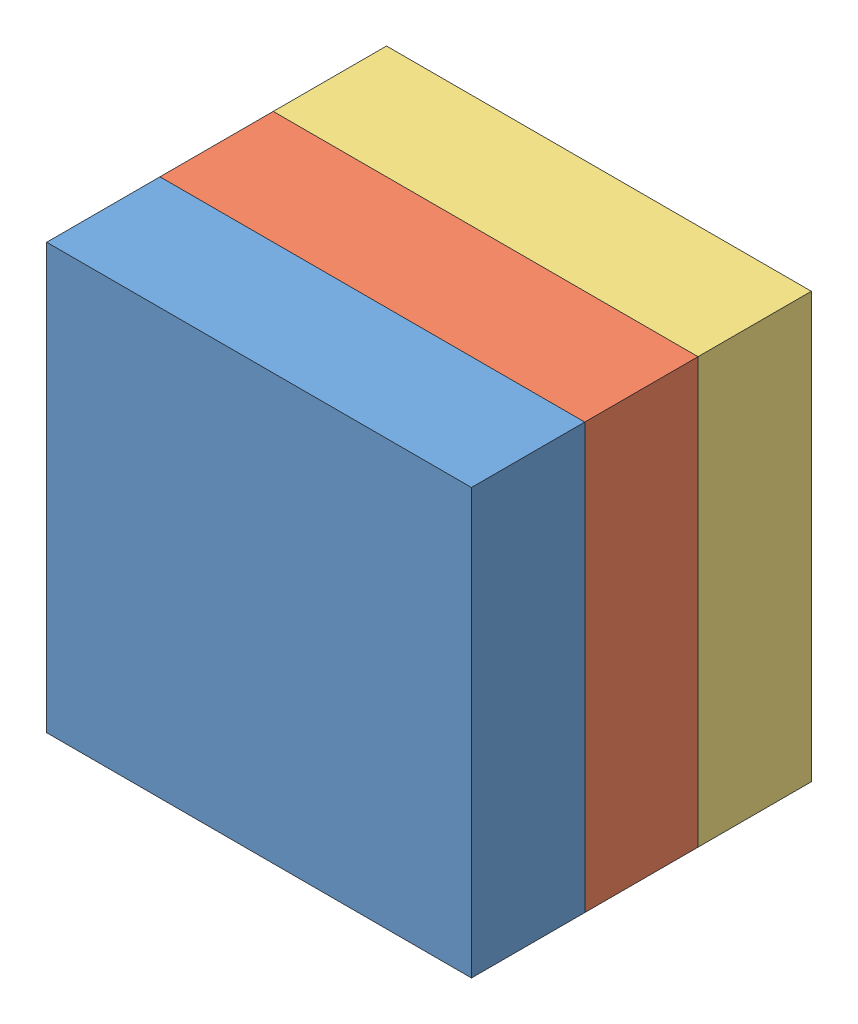
SolidWorks assembly Montagem Molde, configuration Valor predeterminado. Lengths in mm.
Overall size (150 150 120).
147 component instances, 4 part files, 12 mates.
Components (placement in the parent):
- Placa Móvel-1: Placa Móvel [Valor predeterminado] at (-150 0 -40) size (150 150 40)
- Placa Flutuante-1: Placa Flutuante [Valor predeterminado] at (-150 0 -80) size (150 150 40)
- Placa Fixa-1: Placa Fixa [Valor predeterminado] at (-150 0 -120) size (150 150 40)
- Espaçador Escala Maior-1: Espaçador Escala Maior [Valor predeterminado] at (-138.25 138.25 -40) x (1 0 0) z (0 1 0) size (8.16 8.67 8.16)
- Espaçador Escala Maior-2: Espaçador Escala Maior [Valor predeterminado] at (-126.75 138.25 -40) x (1 0 0) z (0 1 0) size (8.16 8.67 8.16)
- Espaçador Escala Maior-3: Espaçador Escala Maior [Valor predeterminado] at (-115.25 138.25 -40) x (1 0 0) z (0 1 0) size (8.16 8.67 8.16)
- Espaçador Escala Maior-4: Espaçador Escala Maior [Valor predeterminado] at (-103.75 138.25 -40) x (1 0 0) z (0 1 0) size (8.16 8.67 8.16)
- Espaçador Escala Maior-5: Espaçador Escala Maior [Valor predeterminado] at (-92.25 138.25 -40) x (1 0 0) z (0 1 0) size (8.16 8.67 8.16)
- Espaçador Escala Maior-6: Espaçador Escala Maior [Valor predeterminado] at (-80.75 138.25 -40) x (1 0 0) z (0 1 0) size (8.16 8.67 8.16)
- Espaçador Escala Maior-7: Espaçador Escala Maior [Valor predeterminado] at (-69.25 138.25 -40) x (1 0 0) z (0 1 0) size (8.16 8.67 8.16)
- Espaçador Escala Maior-8: Espaçador Escala Maior [Valor predeterminado] at (-57.75 138.25 -40) x (1 0 0) z (0 1 0) size (8.16 8.67 8.16)
- Espaçador Escala Maior-9: Espaçador Escala Maior [Valor predeterminado] at (-46.25 138.25 -40) x (1 0 0) z (0 1 0) size (8.16 8.67 8.16)
- Espaçador Escala Maior-10: Espaçador Escala Maior [Valor predeterminado] at (-34.75 138.25 -40) x (1 0 0) z (0 1 0) size (8.16 8.67 8.16)
- Espaçador Escala Maior-11: Espaçador Escala Maior [Valor predeterminado] at (-23.25 138.25 -40) x (1 0 0) z (0 1 0) size (8.16 8.67 8.16)
- Espaçador Escala Maior-12: Espaçador Escala Maior [Valor predeterminado] at (-11.75 138.25 -40) x (1 0 0) z (0 1 0) size (8.16 8.67 8.16)
- Espaçador Escala Maior-13: Espaçador Escala Maior [Valor predeterminado] at (-138.25 126.75 -40) x (1 0 0) z (0 1 0) size (8.16 8.67 8.16)
- Espaçador Escala Maior-14: Espaçador Escala Maior [Valor predeterminado] at (-126.75 126.75 -40) x (1 0 0) z (0 1 0) size (8.16 8.67 8.16)
- Espaçador Escala Maior-15: Espaçador Escala Maior [Valor predeterminado] at (-115.25 126.75 -40) x (1 0 0) z (0 1 0) size (8.16 8.67 8.16)
- Espaçador Escala Maior-16: Espaçador Escala Maior [Valor predeterminado] at (-103.75 126.75 -40) x (1 0 0) z (0 1 0) size (8.16 8.67 8.16)
- Espaçador Escala Maior-17: Espaçador Escala Maior [Valor predeterminado] at (-92.25 126.75 -40) x (1 0 0) z (0 1 0) size (8.16 8.67 8.16)
- Espaçador Escala Maior-18: Espaçador Escala Maior [Valor predeterminado] at (-80.75 126.75 -40) x (1 0 0) z (0 1 0) size (8.16 8.67 8.16)
- Espaçador Escala Maior-19: Espaçador Escala Maior [Valor predeterminado] at (-69.25 126.75 -40) x (1 0 0) z (0 1 0) size (8.16 8.67 8.16)
- Espaçador Escala Maior-20: Espaçador Escala Maior [Valor predeterminado] at (-57.75 126.75 -40) x (1 0 0) z (0 1 0) size (8.16 8.67 8.16)
- Espaçador Escala Maior-21: Espaçador Escala Maior [Valor predeterminado] at (-46.25 126.75 -40) x (1 0 0) z (0 1 0) size (8.16 8.67 8.16)
- Espaçador Escala Maior-22: Espaçador Escala Maior [Valor predeterminado] at (-34.75 126.75 -40) x (1 0 0) z (0 1 0) size (8.16 8.67 8.16)
- Espaçador Escala Maior-23: Espaçador Escala Maior [Valor predeterminado] at (-23.25 126.75 -40) x (1 0 0) z (0 1 0) size (8.16 8.67 8.16)
- Espaçador Escala Maior-24: Espaçador Escala Maior [Valor predeterminado] at (-11.75 126.75 -40) x (1 0 0) z (0 1 0) size (8.16 8.67 8.16)
- Espaçador Escala Maior-25: Espaçador Escala Maior [Valor predeterminado] at (-138.25 115.25 -40) x (1 0 0) z (0 1 0) size (8.16 8.67 8.16)
- Espaçador Escala Maior-26: Espaçador Escala Maior [Valor predeterminado] at (-126.75 115.25 -40) x (1 0 0) z (0 1 0) size (8.16 8.67 8.16)
- Espaçador Escala Maior-27: Espaçador Escala Maior [Valor predeterminado] at (-115.25 115.25 -40) x (1 0 0) z (0 1 0) size (8.16 8.67 8.16)
- Espaçador Escala Maior-28: Espaçador Escala Maior [Valor predeterminado] at (-103.75 115.25 -40) x (1 0 0) z (0 1 0) size (8.16 8.67 8.16)
- Espaçador Escala Maior-29: Espaçador Escala Maior [Valor predeterminado] at (-92.25 115.25 -40) x (1 0 0) z (0 1 0) size (8.16 8.67 8.16)
- Espaçador Escala Maior-30: Espaçador Escala Maior [Valor predeterminado] at (-80.75 115.25 -40) x (1 0 0) z (0 1 0) size (8.16 8.67 8.16)
- Espaçador Escala Maior-31: Espaçador Escala Maior [Valor predeterminado] at (-69.25 115.25 -40) x (1 0 0) z (0 1 0) size (8.16 8.67 8.16)
- Espaçador Escala Maior-32: Espaçador Escala Maior [Valor predeterminado] at (-57.75 115.25 -40) x (1 0 0) z (0 1 0) size (8.16 8.67 8.16)
- Espaçador Escala Maior-33: Espaçador Escala Maior [Valor predeterminado] at (-46.25 115.25 -40) x (1 0 0) z (0 1 0) size (8.16 8.67 8.16)
- Espaçador Escala Maior-34: Espaçador Escala Maior [Valor predeterminado] at (-34.75 115.25 -40) x (1 0 0) z (0 1 0) size (8.16 8.67 8.16)
- Espaçador Escala Maior-35: Espaçador Escala Maior [Valor predeterminado] at (-23.25 115.25 -40) x (1 0 0) z (0 1 0) size (8.16 8.67 8.16)
- Espaçador Escala Maior-36: Espaçador Escala Maior [Valor predeterminado] at (-11.75 115.25 -40) x (1 0 0) z (0 1 0) size (8.16 8.67 8.16)
- Espaçador Escala Maior-37: Espaçador Escala Maior [Valor predeterminado] at (-138.25 103.75 -40) x (1 0 0) z (0 1 0) size (8.16 8.67 8.16)
- Espaçador Escala Maior-38: Espaçador Escala Maior [Valor predeterminado] at (-126.75 103.75 -40) x (1 0 0) z (0 1 0) size (8.16 8.67 8.16)
- Espaçador Escala Maior-39: Espaçador Escala Maior [Valor predeterminado] at (-115.25 103.75 -40) x (1 0 0) z (0 1 0) size (8.16 8.67 8.16)
- Espaçador Escala Maior-40: Espaçador Escala Maior [Valor predeterminado] at (-103.75 103.75 -40) x (1 0 0) z (0 1 0) size (8.16 8.67 8.16)
- Espaçador Escala Maior-41: Espaçador Escala Maior [Valor predeterminado] at (-92.25 103.75 -40) x (1 0 0) z (0 1 0) size (8.16 8.67 8.16)
- Espaçador Escala Maior-42: Espaçador Escala Maior [Valor predeterminado] at (-80.75 103.75 -40) x (1 0 0) z (0 1 0) size (8.16 8.67 8.16)
- Espaçador Escala Maior-43: Espaçador Escala Maior [Valor predeterminado] at (-69.25 103.75 -40) x (1 0 0) z (0 1 0) size (8.16 8.67 8.16)
- Espaçador Escala Maior-44: Espaçador Escala Maior [Valor predeterminado] at (-57.75 103.75 -40) x (1 0 0) z (0 1 0) size (8.16 8.67 8.16)
- Espaçador Escala Maior-45: Espaçador Escala Maior [Valor predeterminado] at (-46.25 103.75 -40) x (1 0 0) z (0 1 0) size (8.16 8.67 8.16)
- Espaçador Escala Maior-46: Espaçador Escala Maior [Valor predeterminado] at (-34.75 103.75 -40) x (1 0 0) z (0 1 0) size (8.16 8.67 8.16)
- Espaçador Escala Maior-47: Espaçador Escala Maior [Valor predeterminado] at (-23.25 103.75 -40) x (1 0 0) z (0 1 0) size (8.16 8.67 8.16)
- Espaçador Escala Maior-48: Espaçador Escala Maior [Valor predeterminado] at (-11.75 103.75 -40) x (1 0 0) z (0 1 0) size (8.16 8.67 8.16)
- Espaçador Escala Maior-49: Espaçador Escala Maior [Valor predeterminado] at (-138.25 92.25 -40) x (1 0 0) z (0 1 0) size (8.16 8.67 8.16)
- Espaçador Escala Maior-50: Espaçador Escala Maior [Valor predeterminado] at (-126.75 92.25 -40) x (1 0 0) z (0 1 0) size (8.16 8.67 8.16)
- Espaçador Escala Maior-51: Espaçador Escala Maior [Valor predeterminado] at (-115.25 92.25 -40) x (1 0 0) z (0 1 0) size (8.16 8.67 8.16)
- Espaçador Escala Maior-52: Espaçador Escala Maior [Valor predeterminado] at (-103.75 92.25 -40) x (1 0 0) z (0 1 0) size (8.16 8.67 8.16)
- Espaçador Escala Maior-53: Espaçador Escala Maior [Valor predeterminado] at (-92.25 92.25 -40) x (1 0 0) z (0 1 0) size (8.16 8.67 8.16)
- Espaçador Escala Maior-54: Espaçador Escala Maior [Valor predeterminado] at (-80.75 92.25 -40) x (1 0 0) z (0 1 0) size (8.16 8.67 8.16)
- Espaçador Escala Maior-55: Espaçador Escala Maior [Valor predeterminado] at (-69.25 92.25 -40) x (1 0 0) z (0 1 0) size (8.16 8.67 8.16)
- Espaçador Escala Maior-56: Espaçador Escala Maior [Valor predeterminado] at (-57.75 92.25 -40) x (1 0 0) z (0 1 0) size (8.16 8.67 8.16)
- Espaçador Escala Maior-57: Espaçador Escala Maior [Valor predeterminado] at (-46.25 92.25 -40) x (1 0 0) z (0 1 0) size (8.16 8.67 8.16)
- Espaçador Escala Maior-58: Espaçador Escala Maior [Valor predeterminado] at (-34.75 92.25 -40) x (1 0 0) z (0 1 0) size (8.16 8.67 8.16)
- Espaçador Escala Maior-59: Espaçador Escala Maior [Valor predeterminado] at (-23.25 92.25 -40) x (1 0 0) z (0 1 0) size (8.16 8.67 8.16)
- Espaçador Escala Maior-60: Espaçador Escala Maior [Valor predeterminado] at (-11.75 92.25 -40) x (1 0 0) z (0 1 0) size (8.16 8.67 8.16)
- Espaçador Escala Maior-61: Espaçador Escala Maior [Valor predeterminado] at (-138.25 80.75 -40) x (1 0 0) z (0 1 0) size (8.16 8.67 8.16)
- Espaçador Escala Maior-62: Espaçador Escala Maior [Valor predeterminado] at (-126.75 80.75 -40) x (1 0 0) z (0 1 0) size (8.16 8.67 8.16)
- Espaçador Escala Maior-63: Espaçador Escala Maior [Valor predeterminado] at (-115.25 80.75 -40) x (1 0 0) z (0 1 0) size (8.16 8.67 8.16)
- Espaçador Escala Maior-64: Espaçador Escala Maior [Valor predeterminado] at (-103.75 80.75 -40) x (1 0 0) z (0 1 0) size (8.16 8.67 8.16)
- Espaçador Escala Maior-65: Espaçador Escala Maior [Valor predeterminado] at (-92.25 80.75 -40) x (1 0 0) z (0 1 0) size (8.16 8.67 8.16)
- Espaçador Escala Maior-66: Espaçador Escala Maior [Valor predeterminado] at (-80.75 80.75 -40) x (1 0 0) z (0 1 0) size (8.16 8.67 8.16)
- Espaçador Escala Maior-67: Espaçador Escala Maior [Valor predeterminado] at (-69.25 80.75 -40) x (1 0 0) z (0 1 0) size (8.16 8.67 8.16)
- Espaçador Escala Maior-68: Espaçador Escala Maior [Valor predeterminado] at (-57.75 80.75 -40) x (1 0 0) z (0 1 0) size (8.16 8.67 8.16)
- Espaçador Escala Maior-69: Espaçador Escala Maior [Valor predeterminado] at (-46.25 80.75 -40) x (1 0 0) z (0 1 0) size (8.16 8.67 8.16)
- Espaçador Escala Maior-70: Espaçador Escala Maior [Valor predeterminado] at (-34.75 80.75 -40) x (1 0 0) z (0 1 0) size (8.16 8.67 8.16)
- Espaçador Escala Maior-71: Espaçador Escala Maior [Valor predeterminado] at (-23.25 80.75 -40) x (1 0 0) z (0 1 0) size (8.16 8.67 8.16)
- Espaçador Escala Maior-72: Espaçador Escala Maior [Valor predeterminado] at (-11.75 80.75 -40) x (1 0 0) z (0 1 0) size (8.16 8.67 8.16)
- Espaçador Escala Maior-73: Espaçador Escala Maior [Valor predeterminado] at (-138.25 69.25 -40) x (1 0 0) z (0 1 0) size (8.16 8.67 8.16)
- Espaçador Escala Maior-74: Espaçador Escala Maior [Valor predeterminado] at (-126.75 69.25 -40) x (1 0 0) z (0 1 0) size (8.16 8.67 8.16)
- Espaçador Escala Maior-75: Espaçador Escala Maior [Valor predeterminado] at (-115.25 69.25 -40) x (1 0 0) z (0 1 0) size (8.16 8.67 8.16)
- Espaçador Escala Maior-76: Espaçador Escala Maior [Valor predeterminado] at (-103.75 69.25 -40) x (1 0 0) z (0 1 0) size (8.16 8.67 8.16)
- Espaçador Escala Maior-77: Espaçador Escala Maior [Valor predeterminado] at (-92.25 69.25 -40) x (1 0 0) z (0 1 0) size (8.16 8.67 8.16)
- Espaçador Escala Maior-78: Espaçador Escala Maior [Valor predeterminado] at (-80.75 69.25 -40) x (1 0 0) z (0 1 0) size (8.16 8.67 8.16)
- Espaçador Escala Maior-79: Espaçador Escala Maior [Valor predeterminado] at (-69.25 69.25 -40) x (1 0 0) z (0 1 0) size (8.16 8.67 8.16)
- Espaçador Escala Maior-80: Espaçador Escala Maior [Valor predeterminado] at (-57.75 69.25 -40) x (1 0 0) z (0 1 0) size (8.16 8.67 8.16)
- Espaçador Escala Maior-81: Espaçador Escala Maior [Valor predeterminado] at (-46.25 69.25 -40) x (1 0 0) z (0 1 0) size (8.16 8.67 8.16)
- Espaçador Escala Maior-82: Espaçador Escala Maior [Valor predeterminado] at (-34.75 69.25 -40) x (1 0 0) z (0 1 0) size (8.16 8.67 8.16)
- Espaçador Escala Maior-83: Espaçador Escala Maior [Valor predeterminado] at (-23.25 69.25 -40) x (1 0 0) z (0 1 0) size (8.16 8.67 8.16)
- Espaçador Escala Maior-84: Espaçador Escala Maior [Valor predeterminado] at (-11.75 69.25 -40) x (1 0 0) z (0 1 0) size (8.16 8.67 8.16)
- Espaçador Escala Maior-85: Espaçador Escala Maior [Valor predeterminado] at (-138.25 57.75 -40) x (1 0 0) z (0 1 0) size (8.16 8.67 8.16)
- Espaçador Escala Maior-86: Espaçador Escala Maior [Valor predeterminado] at (-126.75 57.75 -40) x (1 0 0) z (0 1 0) size (8.16 8.67 8.16)
- Espaçador Escala Maior-87: Espaçador Escala Maior [Valor predeterminado] at (-115.25 57.75 -40) x (1 0 0) z (0 1 0) size (8.16 8.67 8.16)
- Espaçador Escala Maior-88: Espaçador Escala Maior [Valor predeterminado] at (-103.75 57.75 -40) x (1 0 0) z (0 1 0) size (8.16 8.67 8.16)
- Espaçador Escala Maior-89: Espaçador Escala Maior [Valor predeterminado] at (-92.25 57.75 -40) x (1 0 0) z (0 1 0) size (8.16 8.67 8.16)
- Espaçador Escala Maior-90: Espaçador Escala Maior [Valor predeterminado] at (-80.75 57.75 -40) x (1 0 0) z (0 1 0) size (8.16 8.67 8.16)
- Espaçador Escala Maior-91: Espaçador Escala Maior [Valor predeterminado] at (-69.25 57.75 -40) x (1 0 0) z (0 1 0) size (8.16 8.67 8.16)
- Espaçador Escala Maior-92: Espaçador Escala Maior [Valor predeterminado] at (-57.75 57.75 -40) x (1 0 0) z (0 1 0) size (8.16 8.67 8.16)
- Espaçador Escala Maior-93: Espaçador Escala Maior [Valor predeterminado] at (-46.25 57.75 -40) x (1 0 0) z (0 1 0) size (8.16 8.67 8.16)
- Espaçador Escala Maior-94: Espaçador Escala Maior [Valor predeterminado] at (-34.75 57.75 -40) x (1 0 0) z (0 1 0) size (8.16 8.67 8.16)
- Espaçador Escala Maior-95: Espaçador Escala Maior [Valor predeterminado] at (-23.25 57.75 -40) x (1 0 0) z (0 1 0) size (8.16 8.67 8.16)
- Espaçador Escala Maior-96: Espaçador Escala Maior [Valor predeterminado] at (-11.75 57.75 -40) x (1 0 0) z (0 1 0) size (8.16 8.67 8.16)
- Espaçador Escala Maior-97: Espaçador Escala Maior [Valor predeterminado] at (-138.25 46.25 -40) x (1 0 0) z (0 1 0) size (8.16 8.67 8.16)
- Espaçador Escala Maior-98: Espaçador Escala Maior [Valor predeterminado] at (-126.75 46.25 -40) x (1 0 0) z (0 1 0) size (8.16 8.67 8.16)
- Espaçador Escala Maior-99: Espaçador Escala Maior [Valor predeterminado] at (-115.25 46.25 -40) x (1 0 0) z (0 1 0) size (8.16 8.67 8.16)
- Espaçador Escala Maior-100: Espaçador Escala Maior [Valor predeterminado] at (-103.75 46.25 -40) x (1 0 0) z (0 1 0) size (8.16 8.67 8.16)
- Espaçador Escala Maior-101: Espaçador Escala Maior [Valor predeterminado] at (-92.25 46.25 -40) x (1 0 0) z (0 1 0) size (8.16 8.67 8.16)
- Espaçador Escala Maior-102: Espaçador Escala Maior [Valor predeterminado] at (-80.75 46.25 -40) x (1 0 0) z (0 1 0) size (8.16 8.67 8.16)
- Espaçador Escala Maior-103: Espaçador Escala Maior [Valor predeterminado] at (-69.25 46.25 -40) x (1 0 0) z (0 1 0) size (8.16 8.67 8.16)
- Espaçador Escala Maior-104: Espaçador Escala Maior [Valor predeterminado] at (-57.75 46.25 -40) x (1 0 0) z (0 1 0) size (8.16 8.67 8.16)
- Espaçador Escala Maior-105: Espaçador Escala Maior [Valor predeterminado] at (-46.25 46.25 -40) x (1 0 0) z (0 1 0) size (8.16 8.67 8.16)
- Espaçador Escala Maior-106: Espaçador Escala Maior [Valor predeterminado] at (-34.75 46.25 -40) x (1 0 0) z (0 1 0) size (8.16 8.67 8.16)
- Espaçador Escala Maior-107: Espaçador Escala Maior [Valor predeterminado] at (-23.25 46.25 -40) x (1 0 0) z (0 1 0) size (8.16 8.67 8.16)
- Espaçador Escala Maior-108: Espaçador Escala Maior [Valor predeterminado] at (-11.75 46.25 -40) x (1 0 0) z (0 1 0) size (8.16 8.67 8.16)
- Espaçador Escala Maior-109: Espaçador Escala Maior [Valor predeterminado] at (-138.25 34.75 -40) x (1 0 0) z (0 1 0) size (8.16 8.67 8.16)
- Espaçador Escala Maior-110: Espaçador Escala Maior [Valor predeterminado] at (-126.75 34.75 -40) x (1 0 0) z (0 1 0) size (8.16 8.67 8.16)
- Espaçador Escala Maior-111: Espaçador Escala Maior [Valor predeterminado] at (-115.25 34.75 -40) x (1 0 0) z (0 1 0) size (8.16 8.67 8.16)
- Espaçador Escala Maior-112: Espaçador Escala Maior [Valor predeterminado] at (-103.75 34.75 -40) x (1 0 0) z (0 1 0) size (8.16 8.67 8.16)
- Espaçador Escala Maior-113: Espaçador Escala Maior [Valor predeterminado] at (-92.25 34.75 -40) x (1 0 0) z (0 1 0) size (8.16 8.67 8.16)
- Espaçador Escala Maior-114: Espaçador Escala Maior [Valor predeterminado] at (-80.75 34.75 -40) x (1 0 0) z (0 1 0) size (8.16 8.67 8.16)
- Espaçador Escala Maior-115: Espaçador Escala Maior [Valor predeterminado] at (-69.25 34.75 -40) x (1 0 0) z (0 1 0) size (8.16 8.67 8.16)
- Espaçador Escala Maior-116: Espaçador Escala Maior [Valor predeterminado] at (-57.75 34.75 -40) x (1 0 0) z (0 1 0) size (8.16 8.67 8.16)
- Espaçador Escala Maior-117: Espaçador Escala Maior [Valor predeterminado] at (-46.25 34.75 -40) x (1 0 0) z (0 1 0) size (8.16 8.67 8.16)
- Espaçador Escala Maior-118: Espaçador Escala Maior [Valor predeterminado] at (-34.75 34.75 -40) x (1 0 0) z (0 1 0) size (8.16 8.67 8.16)
- Espaçador Escala Maior-119: Espaçador Escala Maior [Valor predeterminado] at (-23.25 34.75 -40) x (1 0 0) z (0 1 0) size (8.16 8.67 8.16)
- Espaçador Escala Maior-120: Espaçador Escala Maior [Valor predeterminado] at (-11.75 34.75 -40) x (1 0 0) z (0 1 0) size (8.16 8.67 8.16)
- Espaçador Escala Maior-121: Espaçador Escala Maior [Valor predeterminado] at (-138.25 23.25 -40) x (1 0 0) z (0 1 0) size (8.16 8.67 8.16)
- Espaçador Escala Maior-122: Espaçador Escala Maior [Valor predeterminado] at (-126.75 23.25 -40) x (1 0 0) z (0 1 0) size (8.16 8.67 8.16)
- Espaçador Escala Maior-123: Espaçador Escala Maior [Valor predeterminado] at (-115.25 23.25 -40) x (1 0 0) z (0 1 0) size (8.16 8.67 8.16)
- Espaçador Escala Maior-124: Espaçador Escala Maior [Valor predeterminado] at (-103.75 23.25 -40) x (1 0 0) z (0 1 0) size (8.16 8.67 8.16)
- Espaçador Escala Maior-125: Espaçador Escala Maior [Valor predeterminado] at (-92.25 23.25 -40) x (1 0 0) z (0 1 0) size (8.16 8.67 8.16)
- Espaçador Escala Maior-126: Espaçador Escala Maior [Valor predeterminado] at (-80.75 23.25 -40) x (1 0 0) z (0 1 0) size (8.16 8.67 8.16)
- Espaçador Escala Maior-127: Espaçador Escala Maior [Valor predeterminado] at (-69.25 23.25 -40) x (1 0 0) z (0 1 0) size (8.16 8.67 8.16)
- Espaçador Escala Maior-128: Espaçador Escala Maior [Valor predeterminado] at (-57.75 23.25 -40) x (1 0 0) z (0 1 0) size (8.16 8.67 8.16)
- Espaçador Escala Maior-129: Espaçador Escala Maior [Valor predeterminado] at (-46.25 23.25 -40) x (1 0 0) z (0 1 0) size (8.16 8.67 8.16)
- Espaçador Escala Maior-130: Espaçador Escala Maior [Valor predeterminado] at (-34.75 23.25 -40) x (1 0 0) z (0 1 0) size (8.16 8.67 8.16)
- Espaçador Escala Maior-131: Espaçador Escala Maior [Valor predeterminado] at (-23.25 23.25 -40) x (1 0 0) z (0 1 0) size (8.16 8.67 8.16)
- Espaçador Escala Maior-132: Espaçador Escala Maior [Valor predeterminado] at (-11.75 23.25 -40) x (1 0 0) z (0 1 0) size (8.16 8.67 8.16)
- Espaçador Escala Maior-133: Espaçador Escala Maior [Valor predeterminado] at (-138.25 11.75 -40) x (1 0 0) z (0 1 0) size (8.16 8.67 8.16)
- Espaçador Escala Maior-134: Espaçador Escala Maior [Valor predeterminado] at (-126.75 11.75 -40) x (1 0 0) z (0 1 0) size (8.16 8.67 8.16)
- Espaçador Escala Maior-135: Espaçador Escala Maior [Valor predeterminado] at (-115.25 11.75 -40) x (1 0 0) z (0 1 0) size (8.16 8.67 8.16)
- Espaçador Escala Maior-136: Espaçador Escala Maior [Valor predeterminado] at (-103.75 11.75 -40) x (1 0 0) z (0 1 0) size (8.16 8.67 8.16)
- Espaçador Escala Maior-137: Espaçador Escala Maior [Valor predeterminado] at (-92.25 11.75 -40) x (1 0 0) z (0 1 0) size (8.16 8.67 8.16)
- Espaçador Escala Maior-138: Espaçador Escala Maior [Valor predeterminado] at (-80.75 11.75 -40) x (1 0 0) z (0 1 0) size (8.16 8.67 8.16)
- Espaçador Escala Maior-139: Espaçador Escala Maior [Valor predeterminado] at (-69.25 11.75 -40) x (1 0 0) z (0 1 0) size (8.16 8.67 8.16)
- Espaçador Escala Maior-140: Espaçador Escala Maior [Valor predeterminado] at (-57.75 11.75 -40) x (1 0 0) z (0 1 0) size (8.16 8.67 8.16)
- Espaçador Escala Maior-141: Espaçador Escala Maior [Valor predeterminado] at (-46.25 11.75 -40) x (1 0 0) z (0 1 0) size (8.16 8.67 8.16)
- Espaçador Escala Maior-142: Espaçador Escala Maior [Valor predeterminado] at (-34.75 11.75 -40) x (1 0 0) z (0 1 0) size (8.16 8.67 8.16)
- Espaçador Escala Maior-143: Espaçador Escala Maior [Valor predeterminado] at (-23.25 11.75 -40) x (1 0 0) z (0 1 0) size (8.16 8.67 8.16)
- Espaçador Escala Maior-144: Espaçador Escala Maior [Valor predeterminado] at (-11.75 11.75 -40) x (1 0 0) z (0 1 0) size (8.16 8.67 8.16)
Mates (geometry in assembly coordinates):
- Coincidente1: coincident aligned: plane of Placa Móvel-1 through (-150 0 0) normal (0 0 1)
- Coincidente2: coincident anti-aligned: plane of Placa Móvel-1 through (-150 0 0) normal (0 -1 0)
- Coincidente3: coincident aligned: plane of Placa Móvel-1 through (0 0 0) normal (1 0 0)
- Coincidente4: coincident: plane of Placa Móvel-1 through (-150 0 -40) normal (0 0 -1); plane of Placa Flutuante-1 through (-150 0 -40) normal (0 0 1)
- Coincidente5: coincident: plane of Placa Móvel-1 through (-150 150 0) normal (0 1 0); plane of Placa Flutuante-1 through (-150 150 -40) normal (0 1 0)
- Coincidente6: coincident aligned: plane of Placa Móvel-1 through (-150 0 0) normal (-1 0 0); plane of Placa Flutuante-1 through (-150 0 -40) normal (-1 0 0)
- Coincidente7: coincident anti-aligned: plane of Placa Flutuante-1 through (-150 0 -80) normal (0 0 -1); plane of Placa Fixa-1 through (-150 0 -80) normal (0 0 1)
- Coincidente8: coincident aligned: plane of Placa Flutuante-1 through (-150 150 -40) normal (0 1 0); plane of Placa Fixa-1 through (-150 150 -80) normal (0 1 0)
- Coincidente9: coincident aligned: plane of Placa Flutuante-1 through (-150 0 -40) normal (-1 0 0); plane of Placa Fixa-1 through (-150 0 -80) normal (-1 0 0)
- Coincidente11: coincident aligned: plane of Placa Flutuante-1 through (-150 0 -40) normal (0 0 1); plane of Espaçador Escala Maior-1 through (-141 138.25 -40) normal (0 0 1)
- Distância1: distance = 11.75 mm aligned: plane of Espaçador Escala Maior-1 through (-138.25 138.25 -40) normal (0 1 0); plane of Placa Móvel-1 through (-150 150 0) normal (0 1 0)
- Distância2: distance = 11.75 mm anti-aligned: plane of Espaçador Escala Maior-1 through (-138.25 138.25 -40) normal (1 0 0); plane of Placa Móvel-1 through (-150 0 0) normal (-1 0 0)
